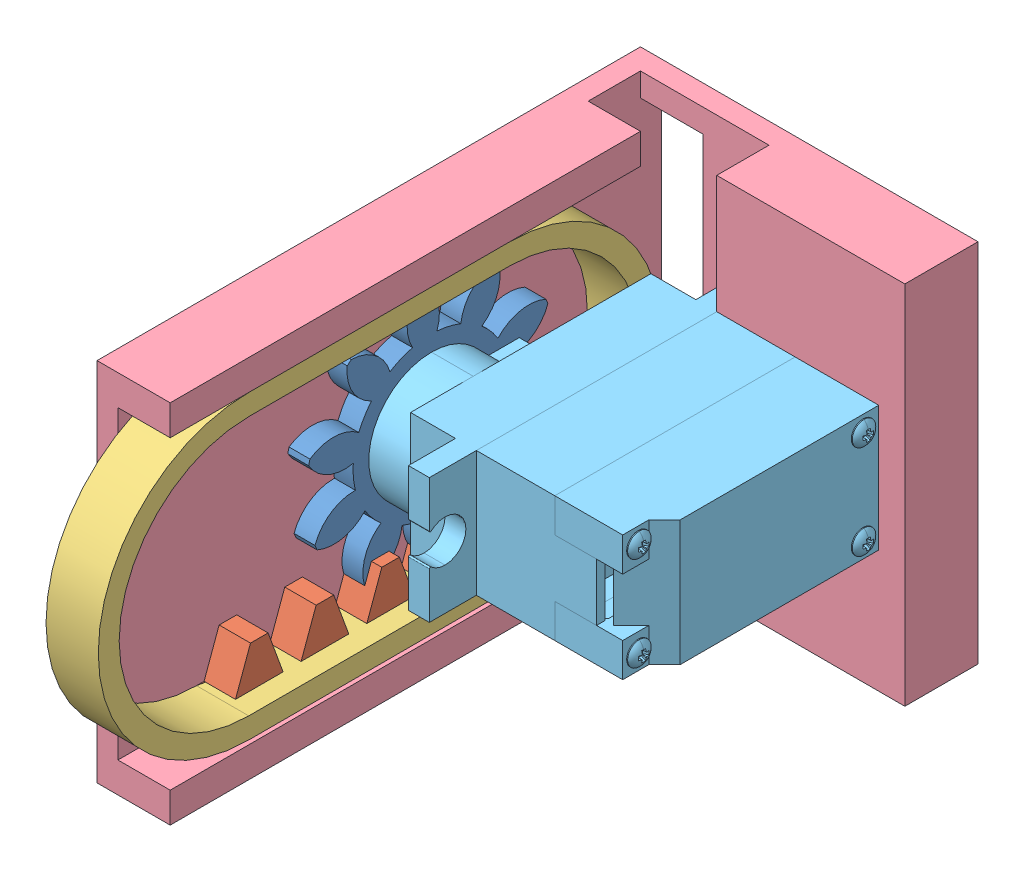
SolidWorks assembly RPTest1, configuration Default. Lengths in mm.
Overall size (32.3 35 58.88).
5 component instances, 5 part files, 11 mates.
Components (placement in the parent):
- spur gear_am1-1: spur gear_am1 [Metric - Spur gear 2M 10T 20PA 2FW ---S10N75H50L5N] at (-23.894 -9.3178 12.0125) x (-1 0 0) z (0 -0.996244 -0.086592) size (2 22.98 24)
- rack spur rectangular_am-1: rack spur rectangular_am [Metric - Rack-spur - rectangular 2M 20PA 3FW 2PH 25L---SAll] at (-25.894 -21.7706 7.4962) x (0 0 1) z (-1 0 0) size (25 4 3)
- loop-1: loop [Default] at (-20.894 -9.3178 32.4962) x (0 0 -1) z (0 1 0) size (53.8 5 28.8)
- TestingRig-1: TestingRig [Default] at (-27.894 7.9822 -11.9875) x (1 0 0) z (0 -1 0) size (32.3 52 35)
- ServoMotor-1: ServoMotor [Default] at (4.546 9.3562 0.0358) x (0 0 1) z (0 -1 0) size (32 28.72 12)
Mates (geometry in assembly coordinates):
- Coincident1: coincident aligned: plane of rack spur rectangular_am-1 through (-22.894 -21.7178 14.6413) normal (0 1 0); plane of loop-1 through (-25.894 -21.7178 32.4962) normal (0 1 0)
- Coincident2: coincident aligned: plane of rack spur rectangular_am-1 through (-25.894 -17.7706 7.4962) normal (-1 0 0); plane of loop-1 through (-25.894 -9.3178 32.4962) normal (-1 0 0)
- Coincident3: coincident anti-aligned: line of rack spur rectangular_am-1 through (-22.894 -21.7178 7.4962) axis (-1 0 0); line of loop-1 through (-25.894 -21.7178 7.4962) axis (1 0 0)
- Coincident5: coincident aligned: plane of spur gear_am-1 through (-25.894 -9.3178 12.0125) normal (-1 0 0); plane of loop-1 through (-25.894 -9.3178 32.4962) normal (-1 0 0)
- Distance1: distance = 12.4 mm: plane of rack spur rectangular_am-1 through (-22.894 -21.7178 14.6413) normal (0 1 0); cylinder of spur gear_am-1 through (-73.8941 -9.3178 12.0125) axis (1 0 0) radius 2.5
- RackPinionMate2: rack pinion = 20 mm: line of loop-1 through (-25.894 -23.7178 7.4962) axis (0 0 1); circle of spur gear_am-1
- Coincident6: coincident anti-aligned: plane of loop-1 through (-25.894 5.0822 32.4962) normal (0 1 0); plane of TestingRig-1 through (-20.894 5.0822 -11.9875) normal (0 -1 0)
- Coincident7: coincident anti-aligned: plane of loop-1 through (-25.894 -9.3178 32.4962) normal (-1 0 0); plane of TestingRig-1 through (-25.894 -27.0178 -11.9875) normal (1 0 0)
- Concentric1: concentric aligned: cylinder of spur gear_am-1 through (-73.8941 -9.3178 12.0125) axis (1 0 0) radius 2.5; cylinder of ServoMotor-1 through (-26.244 -9.3178 12.0125) axis (1 0 0) radius 2.5
- Coincident8: coincident anti-aligned: plane of TestingRig-1 through (-27.894 -27.0178 -4.9875) normal (0 0 1); plane of ServoMotor-1 through (-13.594 -15.3178 -4.9875) normal (0 0 -1)
- Coincident9: coincident anti-aligned: plane of TestingRig-1 through (-13.594 -27.0178 -11.9875) normal (-1 0 0); plane of ServoMotor-1 through (-13.594 -9.3178 6.5125) normal (1 0 0)
